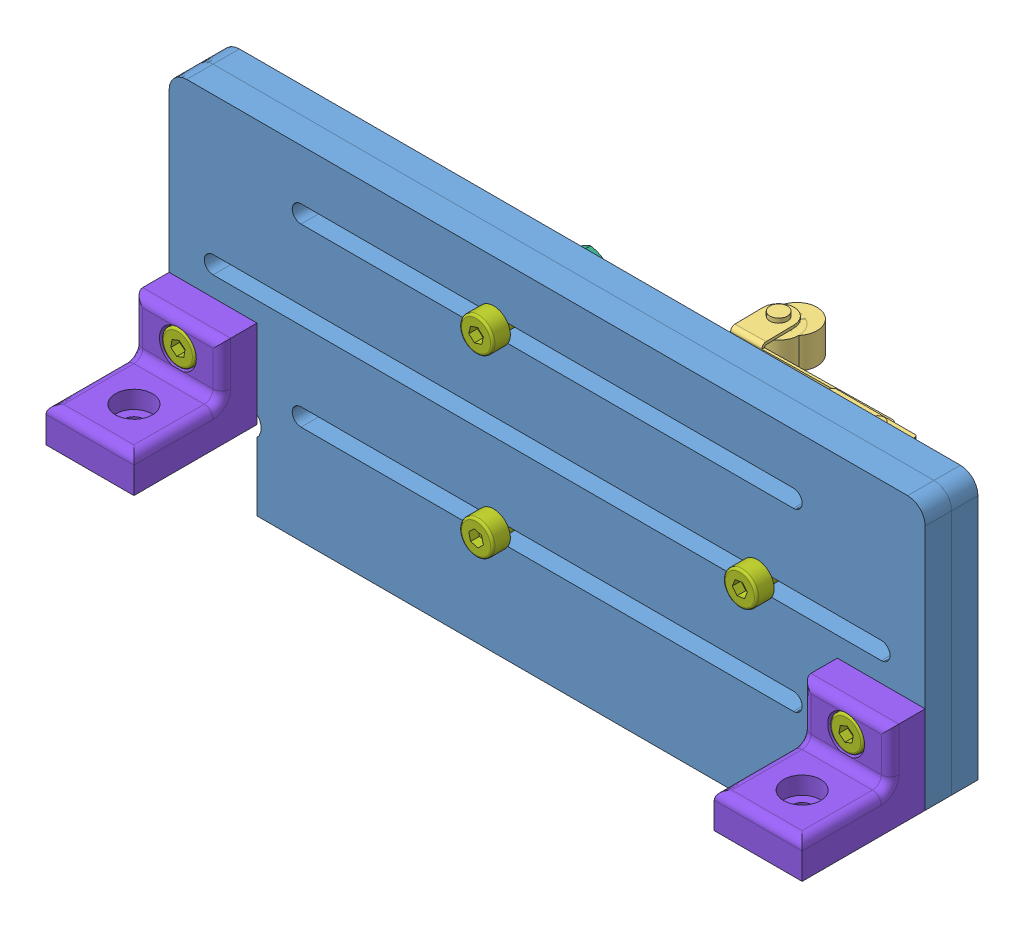
SolidWorks assembly fdc_ferme, configuration Défaut. Lengths in mm.
Overall size (86 39 42.4).
21 component instances, 8 part files, 46 mates.
Components (placement in the parent):
- fdc-platine-1: fdc-platine [Défaut] at (140.8628 -70 0) x (0 0 1) z (0 -1 0) size (3 86 39)
- Grove microswitch v1.0-1: Grove microswitch v1.0 [Défaut] at (-37.098 22.25 -3.344) x (1 0 0) z (0 1 0) size (41.8 22.4 23.6)
  - PCB grove 20x40-1: PCB grove 20x40 [Défaut] at (-1.988 -1.344 0) size (41.8 1.6 23.6)
  - microswitch 10T85-1: microswitch 10T85 [Défaut] at (9.562 0.256 0) size (22.48 22.4 6.4)
  - Connecteur Grove (coudé CMS)-1: Connecteur Grove (coudé CMS) [Défaut] at (-21.488 0.256 0) x (0 0 -1) z (0 1 0) size (12 10 5)
- entretoise-grove-1: entretoise-grove [Défaut] at (-19.086 22.25 -2) x (1 0.000242 0) z (0 0 1) size (4 4 2)
- entretoise-grove-2: entretoise-grove [Défaut] at (-49.086 12.25 -2) size (4 4 2)
- entretoise-grove-3: entretoise-grove [Défaut] at (-49.086 32.25 -2) size (4 4 2)
- ecrou-h-1: ecrou-h [6007 HU M2] at (-19.086 22.25 -3.6) x (0.5 0.866025 0) z (0.866025 -0.5 0) size (4 1.6 4.62)
- ecrou-h-2: ecrou-h [6007 HU M2] at (-49.086 12.25 -3.6) x (1 0 0) z (0 -1 0) size (4 1.6 4.62)
- ecrou-h-3: ecrou-h [6007 HU M2] at (-49.086 32.25 -3.6) x (-0.5 0.866025 0) z (0.866025 0.5 0) size (4 1.6 4.62)
- vis-chc-1: vis-chc [Vis CHC M2x12] at (-49.086 12.25 6) x (0.689734 0.724063 0) z (0.724063 -0.689734 0) size (3.8 14 3.8)
- vis-chc-2: vis-chc [Vis CHC M2x12] at (-49.086 32.25 6) x (-0.193562 -0.981088 0) z (-0.981088 0.193562 0) size (3.8 14 3.8)
- vis-chc-3: vis-chc [Vis CHC M2x12] at (-19.086 22.25 6) x (-0.643508 0.765439 0) z (0.765439 0.643508 0) size (3.8 14 3.8)
- ecrou-h-5: ecrou-h [6007 HU M2] at (-81 16 -1.6) x (1 0 0) z (0 1 0) size (4 1.6 4.62)
- ecrou-h-6: ecrou-h [6007 HU M2] at (-5 16 -1.6) x (1 0 0) z (0 1 0) size (4 1.6 4.62)
- vis-chc-6: vis-chc [Vis CHC M2x10] at (-5 16 8) x (-0.923728 -0.383049 0) z (-0.383049 0.923728 0) size (3.8 12 3.8)
- vis-chc-7: vis-chc [Vis CHC M2x10] at (-81 16 8) x (-0.923728 -0.383049 0) z (-0.383049 0.923728 0) size (3.8 12 3.8)
- fdc-platine-2: fdc-platine [Défaut] at (140.8628 -70 3) x (0 0 1) z (0 -1 0) size (3 86 39)
- equerre-basse-1: equerre-basse [Défaut] at (-81 9 6) size (10 10 14)
- equerre-basse-2: equerre-basse [Défaut] at (-5 9 6) size (10 10 14)
Mates (geometry in assembly coordinates):
- Coïncidente1: coincident anti-aligned: plane of cfc-platine-1 through (-8.8686 8.8686 0) normal (0 0 -1)
- Coïncidente2: coincident anti-aligned: plane of cfc-platine-1 through (-10 0 3) normal (0 -1 0)
- Coaxiale1: concentric anti-aligned: cylinder of Grove microswitch v1.0-1/PCB grove 20x40-1 through (-49.086 32.25 -3.6) axis (0 0 1) radius 1.1; cylinder of entretoise-grove-3 through (-49.086 32.25 0) axis (0 0 -1) radius 1.2
- Coïncidente4: coincident anti-aligned: plane of Grove microswitch v1.0-1/PCB grove 20x40-1 through (-39.086 22.25 -2) normal (0 0 1); plane of entretoise-grove-3 through (-49.086 32.25 -2) normal (0 0 -1)
- Coaxiale2: concentric anti-aligned: cylinder of Grove microswitch v1.0-1/PCB grove 20x40-1 through (-19.086 22.25 -3.6) axis (0 0 1) radius 1.1; cylinder of entretoise-grove-1 through (-19.086 22.25 0) axis (0 0 -1) radius 1.2
- Coïncidente5: coincident anti-aligned: plane of Grove microswitch v1.0-1/PCB grove 20x40-1 through (-39.086 22.25 -2) normal (0 0 1); plane of entretoise-grove-1 through (-19.086 22.25 -2) normal (0 0 -1)
- Coaxiale3: concentric anti-aligned: cylinder of Grove microswitch v1.0-1/PCB grove 20x40-1 through (-49.086 12.25 -3.6) axis (0 0 1) radius 1.1; cylinder of entretoise-grove-2 through (-49.086 12.25 0) axis (0 0 -1) radius 1.2
- Coïncidente6: coincident anti-aligned: plane of Grove microswitch v1.0-1/PCB grove 20x40-1 through (-39.086 22.25 -2) normal (0 0 1); plane of entretoise-grove-2 through (-49.086 12.25 -2) normal (0 0 -1)
- Coïncidente7: coincident anti-aligned: plane of cfc-platine-1 through (-8.8686 8.8686 0) normal (0 0 -1); plane of entretoise-grove-1 through (-19.086 22.25 0) normal (0 0 1)
- Parallèle4: parallel anti-aligned: plane of cfc-platine-1 through (-86 39 3) normal (-1 0 0); plane of Grove microswitch v1.0-1/PCB grove 20x40-1 through (-19.086 22.25 -3.6) normal (1 0 0)
- Parallèle3: parallel anti-aligned: plane of cfc-platine-1 through (-10 0 3) normal (0 -1 0); plane of Grove microswitch v1.0-1/PCB grove 20x40-1 through (-39.086 32.25 -3.6) normal (0 1 0)
- Coaxiale7: concentric aligned: cylinder of ecrou-h-2 through (-49.086 12.25 -5.2) axis (0 0 1) radius 0.7835; cylinder of vis-chc-1 through (-49.086 12.25 -6) axis (0 0 1) radius 1
- Coaxiale8: concentric aligned: cylinder of ecrou-h-3 through (-49.086 32.25 -5.2) axis (0 0 1) radius 0.7835; cylinder of vis-chc-2 through (-49.086 32.25 -6) axis (0 0 1) radius 1
- Coaxiale9: concentric aligned: cylinder of ecrou-h-1 through (-19.086 22.25 -5.2) axis (0 0 1) radius 0.7835; cylinder of vis-chc-3 through (-19.086 22.25 -6) axis (0 0 1) radius 1
- Tangent1: tangent anti-aligned: plane of cfc-platine-1 through (-5 21.25 3) normal (0 1 0); cylinder of vis-chc-3 through (-19.086 22.25 -6) axis (0 0 1) radius 1
- Coïncidente8: coincident anti-aligned: plane of Grove microswitch v1.0-1/PCB grove 20x40-1 through (-39.086 22.25 -3.6) normal (0 0 -1); plane of ecrou-h-1 through (-19.086 24.5594 -3.6) normal (0 0 1)
- Parallèle10: parallel anti-aligned: plane of Grove microswitch v1.0-1/microswitch 10T85-1 through (-21.086 25.25 -13.9) normal (1 0 0); plane of ecrou-h-1 through (-21.086 23.4047 -5.2) normal (-1 0 0)
- Coïncidente11: coincident anti-aligned: plane of Grove microswitch v1.0-1/PCB grove 20x40-1 through (-39.086 22.25 -3.6) normal (0 0 -1); plane of ecrou-h-2 through (-47.086 13.4047 -3.6) normal (0 0 1)
- Parallèle11: parallel anti-aligned: plane of cfc-platine-1 through (-86 39 3) normal (-1 0 0); plane of ecrou-h-2 through (-47.086 11.0953 -5.2) normal (1 0 0)
- Coïncidente13: coincident anti-aligned: plane of Grove microswitch v1.0-1/PCB grove 20x40-1 through (-39.086 22.25 -3.6) normal (0 0 -1); plane of ecrou-h-3 through (-51.086 33.4047 -3.6) normal (0 0 1)
- Parallèle12: parallel aligned: plane of cfc-platine-1 through (-86 39 3) normal (-1 0 0); plane of ecrou-h-3 through (-51.086 33.4047 -5.2) normal (-1 0 0)
- Coïncidente15: coincident anti-aligned: plane of cfc-platine-1 through (-8.8686 8.8686 3) normal (0 0 1); plane of cfc-platine-2 through (-8.8686 8.8686 3) normal (0 0 -1)
- Coïncidente16: coincident aligned: plane of cfc-platine-1 through (-10 0 3) normal (0 -1 0); plane of cfc-platine-2 through (-10 0 6) normal (0 -1 0)
- Coïncidente17: coincident aligned: plane of cfc-platine-1 through (-86 39 3) normal (-1 0 0); plane of cfc-platine-2 through (-86 39 6) normal (-1 0 0)
- Coïncidente19: coincident anti-aligned: plane of vis-chc-2 through (-49.086 32.25 6) normal (0 0 -1); plane of cfc-platine-2 through (-8.8686 8.8686 6) normal (0 0 1)
- Coaxiale10: concentric aligned: cylinder of Grove microswitch v1.0-1/PCB grove 20x40-1 through (-49.086 32.25 -3.6) axis (0 0 1) radius 1.1; cylinder of vis-chc-2 through (-49.086 32.25 -6) axis (0 0 1) radius 1
- Coaxiale11: concentric aligned: cylinder of Grove microswitch v1.0-1/PCB grove 20x40-1 through (-19.086 22.25 -3.6) axis (0 0 1) radius 1.1; cylinder of vis-chc-3 through (-19.086 22.25 -6) axis (0 0 1) radius 1
- Coïncidente21: coincident anti-aligned: plane of vis-chc-3 through (-19.086 22.25 6) normal (0 0 -1); plane of cfc-platine-2 through (-8.8686 8.8686 6) normal (0 0 1)
- Coïncidente22: coincident anti-aligned: plane of vis-chc-1 through (-49.086 12.25 6) normal (0 0 -1); plane of cfc-platine-2 through (-8.8686 8.8686 6) normal (0 0 1)
- Coaxiale12: concentric aligned: cylinder of Grove microswitch v1.0-1/PCB grove 20x40-1 through (-49.086 12.25 -3.6) axis (0 0 1) radius 1.1; cylinder of vis-chc-1 through (-49.086 12.25 -6) axis (0 0 1) radius 1
- Coïncidente23: coincident aligned: plane of cfc-platine-2 through (-78.726 9 6) normal (0 -1 0); plane of equerre-1 through (-86 9 10) normal (0 -1 0)
- Coïncidente24: coincident anti-aligned: plane of cfc-platine-2 through (-8.8686 8.8686 6) normal (0 0 1); plane of equerre-1 through (-81 9 6) normal (0 0 -1)
- Coaxiale13: concentric anti-aligned: cylinder of cfc-platine-2 through (-81 16 6) axis (0 0 -1) radius 1; cylinder of equerre-1 through (-81 16 6) axis (0 0 1) radius 1.1
- Coïncidente25: coincident anti-aligned: plane of cfc-platine-2 through (-8.8686 8.8686 6) normal (0 0 1); plane of equerre-2 through (-5 9 6) normal (0 0 -1)
- Coïncidente26: coincident aligned: plane of cfc-platine-2 through (0 9 6) normal (0 -1 0); plane of equerre-2 through (-10 9 10) normal (0 -1 0)
- Coaxiale14: concentric anti-aligned: cylinder of cfc-platine-2 through (-5 16 6) axis (0 0 -1) radius 1; cylinder of equerre-2 through (-5 16 6) axis (0 0 1) radius 1.1
- Coaxiale16: concentric aligned: cylinder of vis-chc-7 through (-81 16 -2) axis (0 0 1) radius 1; cylinder of equerre-1 through (-81 16 6) axis (0 0 1) radius 1.1
- Coaxiale17: concentric aligned: cylinder of vis-chc-6 through (-5 16 -2) axis (0 0 1) radius 1; cylinder of equerre-2 through (-5 16 6) axis (0 0 1) radius 1.1
- Coïncidente28: coincident anti-aligned: plane of vis-chc-6 through (-5 16 8) normal (0 0 -1); plane of equerre-2 through (-5 16 8) normal (0 0 1)
- Coïncidente29: coincident anti-aligned: plane of vis-chc-7 through (-81 16 8) normal (0 0 -1); plane of equerre-1 through (-81 16 8) normal (0 0 1)
- Coaxiale20: concentric anti-aligned: cylinder of ecrou-h-5 through (-81 16 0) axis (0 0 -1) radius 0.7835; cylinder of vis-chc-7 through (-81 16 -2) axis (0 0 1) radius 1
- Coïncidente33: coincident anti-aligned: plane of cfc-platine-1 through (-8.8686 8.8686 0) normal (0 0 -1); plane of ecrou-h-5 through (-79 14.8453 0) normal (0 0 1)
- Parallèle14: parallel aligned: plane of cfc-platine-1 through (-86 39 3) normal (-1 0 0); plane of ecrou-h-5 through (-83 14.8453 0) normal (-1 0 0)
- Coaxiale22: concentric anti-aligned: cylinder of ecrou-h-6 through (-5 16 0) axis (0 0 -1) radius 0.7835; cylinder of vis-chc-6 through (-5 16 -2) axis (0 0 1) radius 1
- Coïncidente35: coincident anti-aligned: plane of cfc-platine-1 through (-8.8686 8.8686 0) normal (0 0 -1); plane of ecrou-h-6 through (-3 14.8453 0) normal (0 0 1)
- Parallèle15: parallel aligned: plane of cfc-platine-1 through (0 9 3) normal (1 0 0); plane of ecrou-h-6 through (-3 17.1547 0) normal (1 0 0)
